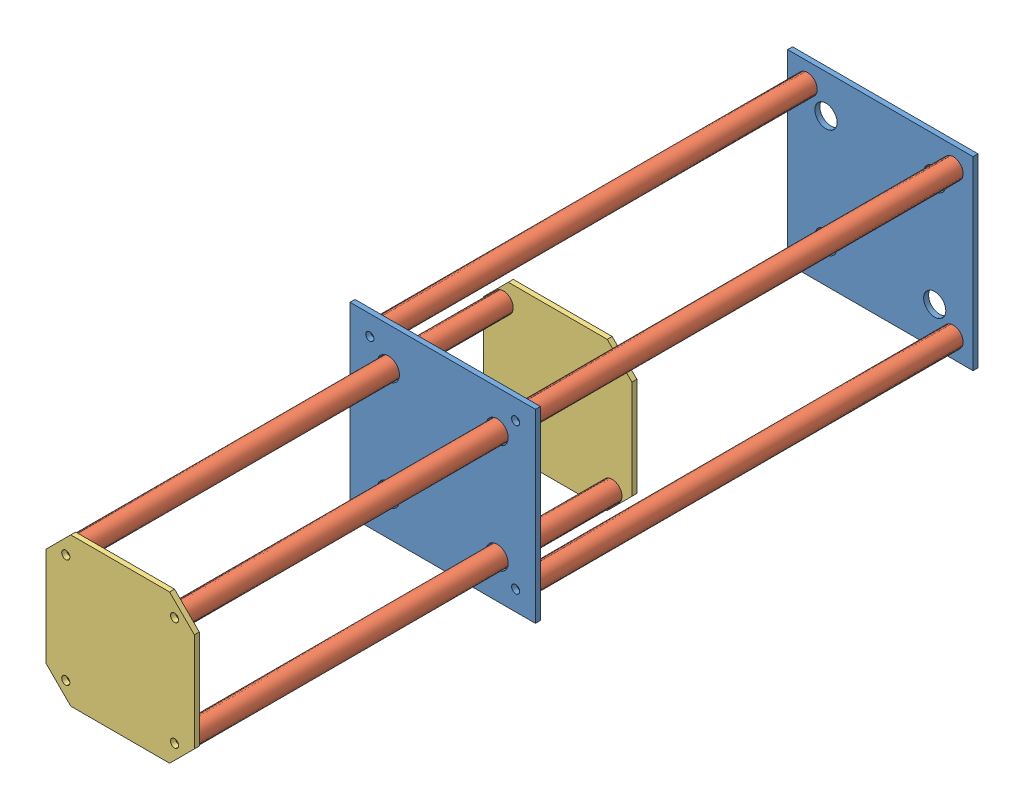
SolidWorks assembly 上下可動部分 改善版, configuration ﾃﾞﾌｫﾙﾄ. Lengths in mm.
Overall size (75 75 309.47).
12 component instances, 3 part files, 32 mates.
Components (placement in the parent):
- 上板-1: 上板 [ﾃﾞﾌｫﾙﾄ] at (-31.5102 12.186 74) size (75 75 2)
- スライド棒-1: スライド棒 [ﾃﾞﾌｫﾙﾄ] at (-61.0102 41.686 163.5) x (-0.647076 0.762426 0) z (0 0 1) size (8 8 175)
- スライド棒-2: スライド棒 [ﾃﾞﾌｫﾙﾄ] at (-2.0102 41.686 163.5) x (0.967939 -0.251187 0) z (0 0 1) size (8 8 175)
- スライド棒-3: スライド棒 [ﾃﾞﾌｫﾙﾄ] at (-2.0102 -17.314 163.5) x (0.975528 0.219873 0) z (0 0 1) size (8 8 175)
- スライド棒-4: スライド棒 [ﾃﾞﾌｫﾙﾄ] at (-61.0102 -17.314 163.5) size (8 8 175)
- 上板-2: 上板 [ﾃﾞﾌｫﾙﾄ] at (-31.5102 12.186 251) size (75 75 2)
- 中板-1: 中板 [ﾃﾞﾌｫﾙﾄ] at (-31.5192 12.177 204.4663) size (60 60 2)
- スライド棒-5: スライド棒 [ﾃﾞﾌｫﾙﾄ] at (-53.5192 -9.823 293.9663) x (-0.887126 0.461526 0) z (0 0 1) size (8 8 175)
- スライド棒-6: スライド棒 [ﾃﾞﾌｫﾙﾄ] at (-9.5192 -9.823 293.9663) x (0.602901 -0.797816 0) z (0 0 1) size (8 8 175)
- スライド棒-7: スライド棒 [ﾃﾞﾌｫﾙﾄ] at (-53.5192 34.177 293.9663) x (0.427104 0.904203 0) z (0 0 1) size (8 8 175)
- スライド棒-8: スライド棒 [ﾃﾞﾌｫﾙﾄ] at (-9.5192 34.177 293.9663) x (-0.638891 -0.769298 0) z (0 0 1) size (8 8 175)
- 中板-2: 中板 [ﾃﾞﾌｫﾙﾄ] at (-31.5192 12.177 381.4663) size (60 60 2)
Mates (geometry in assembly coordinates):
- 同心円1: concentric: cylinder of 上板-1 through (-61.0102 41.686 74) axis (0 0 -1) radius 1.65; cylinder of スライド棒-1 through (-61.0102 41.686 76) axis (0 0 -1) radius 1.65
- 同心円2: concentric: cylinder of 上板-1 through (-61.0102 -17.314 74) axis (0 0 -1) radius 1.65; cylinder of スライド棒-4 through (-61.0102 -17.314 76) axis (0 0 -1) radius 1.65
- 同心円3: concentric: cylinder of 上板-1 through (-2.0102 41.686 74) axis (0 0 -1) radius 1.65; cylinder of スライド棒-2 through (-2.0102 41.686 76) axis (0 0 -1) radius 1.65
- 同心円4: concentric: cylinder of 上板-1 through (-2.0102 -17.314 74) axis (0 0 -1) radius 1.65; cylinder of スライド棒-3 through (-2.0102 -17.314 76) axis (0 0 -1) radius 1.65
- 一致1: coincident: plane of 上板-1 through (-31.5102 12.186 76) normal (0 0 1); plane of スライド棒-3 through (-2.0102 -17.314 76) normal (0 0 -1)
- 一致2: coincident: plane of 上板-1 through (-31.5102 12.186 76) normal (0 0 1); plane of スライド棒-2 through (-2.0102 41.686 76) normal (0 0 -1)
- 一致3: coincident: plane of 上板-1 through (-31.5102 12.186 76) normal (0 0 1); plane of スライド棒-1 through (-61.0102 41.686 76) normal (0 0 -1)
- 一致4: coincident: plane of 上板-1 through (-31.5102 12.186 76) normal (0 0 1); plane of スライド棒-4 through (-61.0102 -17.314 76) normal (0 0 -1)
- 同心円5: concentric: cylinder of スライド棒-1 through (-61.0102 41.686 251) axis (0 0 1) radius 1.65; cylinder of 上板-2 through (-61.0102 41.686 251) axis (0 0 -1) radius 1.65
- 一致5: coincident: circle of スライド棒-4; cylinder of 上板-2 through (-61.0102 -17.314 251) axis (0 0 -1) radius 1.65
- 一致6: coincident: circle of スライド棒-2; cylinder of 上板-2 through (-2.0102 41.686 251) axis (0 0 -1) radius 1.65
- 一致7: coincident: plane of スライド棒-2 through (-2.0102 41.686 251) normal (0 0 1); plane of 上板-2 through (-31.5102 12.186 251) normal (0 0 -1)
- 同心円6: concentric: cylinder of 中板-1 through (-9.5192 34.177 204.4663) axis (0 0 -1) radius 1.65; cylinder of スライド棒-8 through (-9.5192 34.177 206.4663) axis (0 0 -1) radius 1.65
- 同心円7: concentric: cylinder of 中板-1 through (-53.5192 34.177 204.4663) axis (0 0 -1) radius 1.65; cylinder of スライド棒-7 through (-53.5192 34.177 206.4663) axis (0 0 -1) radius 1.65
- 同心円8: concentric: cylinder of 中板-1 through (-53.5192 -9.823 204.4663) axis (0 0 -1) radius 1.65; cylinder of スライド棒-5 through (-53.5192 -9.823 206.4663) axis (0 0 -1) radius 1.65
- 同心円9: concentric: cylinder of 中板-1 through (-9.5192 -9.823 204.4663) axis (0 0 -1) radius 1.65; cylinder of スライド棒-6 through (-9.5192 -9.823 206.4663) axis (0 0 -1) radius 1.65
- 一致8: coincident: plane of 中板-1 through (-31.5192 12.177 206.4663) normal (0 0 1); plane of スライド棒-6 through (-9.5192 -9.823 206.4663) normal (0 0 -1)
- 一致9: coincident: plane of 中板-1 through (-31.5192 12.177 206.4663) normal (0 0 1); plane of スライド棒-5 through (-53.5192 -9.823 206.4663) normal (0 0 -1)
- 一致10: coincident: plane of 中板-1 through (-31.5192 12.177 206.4663) normal (0 0 1); plane of スライド棒-7 through (-53.5192 34.177 206.4663) normal (0 0 -1)
- 一致11: coincident: plane of 中板-1 through (-31.5192 12.177 206.4663) normal (0 0 1); plane of スライド棒-8 through (-9.5192 34.177 206.4663) normal (0 0 -1)
- 同心円10: concentric: cylinder of 上板-2 through (-9.5192 34.177 331) axis (0 0 -1) radius 4.5; cylinder of スライド棒-8 through (-9.5192 34.177 381.4663) axis (0 0 -1) radius 4
- 平行1: parallel: cylinder of 上板-2 through (-53.5012 -9.805 331) axis (0 0 -1) radius 4.5; cylinder of スライド棒-5 through (-53.5192 -9.823 381.4663) axis (0 0 -1) radius 4
- 平行3: parallel: plane of 上板-2 through (-69.0102 49.686 253) normal (0 1 0); plane of 中板-1 through (-61.5192 42.177 206.4663) normal (0 1 0)
- 同心円13: concentric: cylinder of スライド棒-7 through (-53.5192 34.177 381.4663) axis (0 0 -1) radius 4; cylinder of 中板-2 through (-53.5192 34.177 381.4663) axis (0 0 -1) radius 1.65
- 同心円14: concentric: cylinder of スライド棒-6 through (-9.5192 -9.823 381.4663) axis (0 0 1) radius 1.65; cylinder of 中板-2 through (-9.5192 -9.823 381.4663) axis (0 0 -1) radius 1.65
- 一致13: coincident: plane of スライド棒-5 through (-53.5192 -9.823 381.4663) normal (0 0 1); plane of 中板-2 through (-31.5192 12.177 381.4663) normal (0 0 -1)
- 同心円16: concentric: cylinder of スライド棒-7 through (-53.5192 34.177 271.9) axis (0 0 -1) radius 4; circle of ?
- 同心円17: concentric: cylinder of スライド棒-5 through (-53.5192 -9.823 271.9) axis (0 0 -1) radius 4; cylinder of ? through (-53.5192 -9.823 211.9) axis (0 0 1) radius 4.5
- 一致15: coincident: plane of 中板-2 through (-31.5192 12.177 271.9) normal (0 0 -1); plane of ? through (-61.0192 -37.823 271.9) normal (0 0 1)
- 同心円18: concentric: cylinder of スライド棒-8 through (-9.5192 34.177 419.8705) axis (0 0 -1) radius 4; cylinder of ? through (-9.5192 34.177 359.8705) axis (0 0 1) radius 4.5
- 同心円19: concentric: cylinder of スライド棒-6 through (-9.5192 -9.823 419.8705) axis (0 0 -1) radius 4; cylinder of ? through (-9.5192 -9.823 359.8705) axis (0 0 1) radius 4.5
- 一致16: coincident: plane of 中板-2 through (-31.5192 12.177 419.8705) normal (0 0 -1); plane of ? through (-17.0192 -37.823 419.8705) normal (0 0 1)
